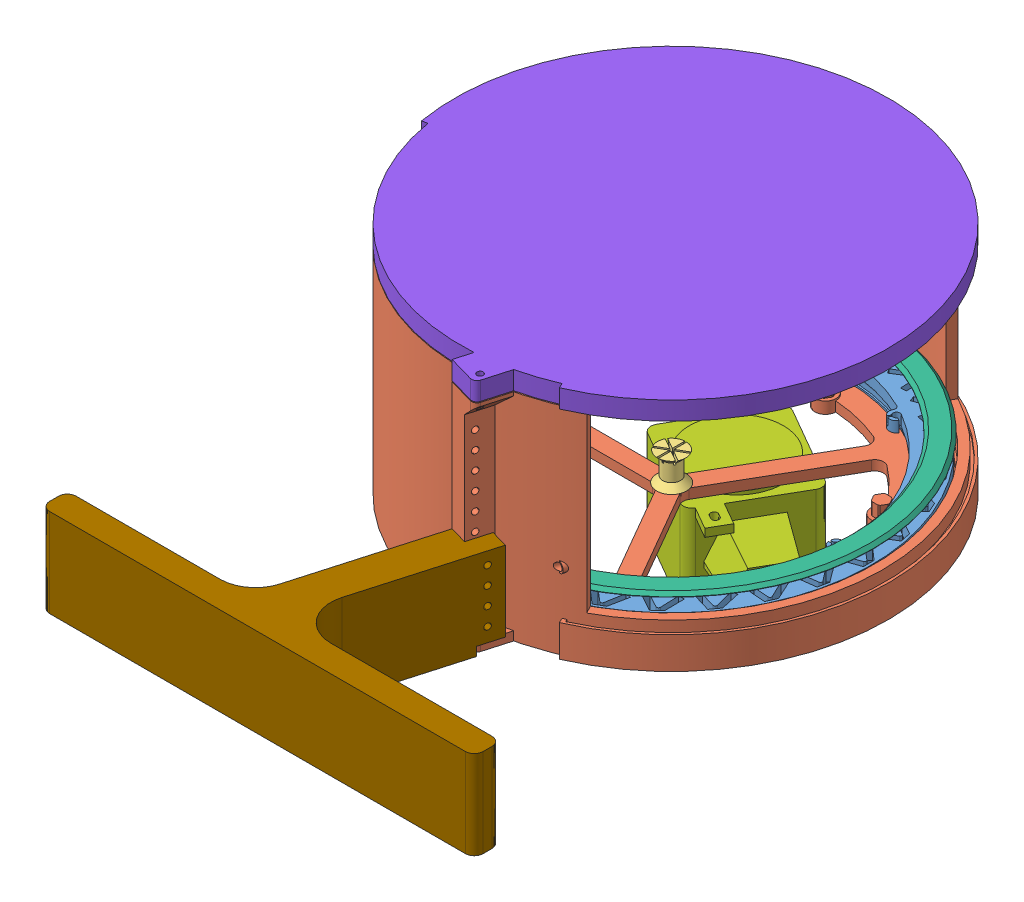
SolidWorks assembly 多色模块-装配体, configuration 默认. Lengths in mm.
Overall size (362.98 195.67 356.44).
17 component instances, 16 part files, 16 mates.
Components (placement in the parent):
- 卡爪-1: 卡爪 [默认] at origin size (224.72 94.33 198.11) (hidden)
- 托盘-2: 托盘 [默认] at origin size (225.72 151.25 225.72)
- 外筒-1: 外筒 [默认] at origin size (293.71 127.25 345.86)
- 外筒-2: 外筒 [默认] at (0 122.153 0) size (293.71 127.25 345.86) (hidden)
- 门-1: 门 [默认] at origin size (74.09 107 231.08) (hidden)
- 回转爪-1: 回转爪 [默认] at origin size (352.65 71.3 16.8)
- 阻尼轴-2: 阻尼轴 [默认] at (-0.2 -13 -0.1155) size (5.5 7 6.35)
- 608轴承-1: 608轴承 [默认] at (-75.2595 -15.2 -43.4511) size (22 42.33 22)
- 挡环-1: 挡环 [默认] at origin size (227.52 2 227.52)
- 模块化挤出机-1: 模块化挤出机 [默认] at (5.5296 17 187.6364) x (0 1 0) z (-0.275449 0 0.961316) size (62.4 10 62.4) (hidden)
- CR20挤出机-1: CR20挤出机 [默认] at (5.5296 17 187.6364) x (0.275449 0 -0.961316) z (0 -1 0) size (72 25 57) (hidden)
- 挤出机连接-1: 挤出机连接 [默认] at origin size (20.98 123.75 48.47) (hidden)
- 挤出机支撑-1: 挤出机支撑 [默认] at origin
- Octopus_Pro - beta简化-1: Octopus_Pro - beta简化 [默认] at (-539.2933 -519.147 155.4731) size (162.15 99.88 19.4) (hidden)
- ptc-1: ptc [默认] at (-12.2337 -33.953 -48.8105) x (-0.866025 0 -0.5) z (0.5 0 -0.866025) size (103 52 60)
- 盖-1: 盖 [默认] at origin size (244.92 10.4 255.45)
- 底座增稳-1: 底座增稳 [默认] at origin size (244.92 50 115)
Mates (geometry in assembly coordinates):
- 距离1: distance = 0.2 mm anti-aligned: plane of 外筒-1 through (-114.3607 100 0) normal (0 1 0); plane of 外筒-2 through (-119.3607 100.2 0) normal (0 -1 0)
- 距离3: distance = 0.2 mm anti-aligned: plane of 外筒-1 through (0 -20.2 0) normal (0 1 0); plane of 阻尼轴-2 through (-0.2 -20 -0.1155) normal (0 -1 0)
- 距离4: distance = 0.2 mm anti-aligned: plane of 外筒-1 through (0 -20.2 3.1754) normal (-0.5 0 -0.866025); plane of 阻尼轴-2 through (2.55 -20 1.4722) normal (0.5 0 0.866025)
- 距离5: distance = 0.2 mm anti-aligned: plane of 外筒-1 through (2.75 -20.2 1.5877) normal (-1 0 0); plane of 阻尼轴-2 through (2.55 -20 -1.7032) normal (1 0 0)
- 距离9: distance = 0.2 mm anti-aligned: plane of 外筒-1 through (-75.2595 -15.4 -43.4511) normal (0 1 0); plane of 608轴承-1 through (-79.2595 -15.2 -43.4511) normal (0 -1 0)
- 同心2: concentric aligned: cylinder of 外筒-1 through (-75.2595 -38.9235 -43.4511) axis (0 1 0) radius 6; cylinder of 608轴承-1 through (-75.2595 4.1457 -43.4511) axis (0 1 0) radius 4
- 同心3: concentric aligned: cylinder of 外筒-1 through (0 0 0) axis (0 1 0) radius 114.3607; cylinder of 外筒-2 through (0 122.153 0) axis (0 1 0) radius 114.3607
- 平行1: parallel anti-aligned: plane of 外筒-1 through (-33.7317 0 117.7234) normal (-0.275449 0 0.961316); plane of 模块化挤出机-1 through (4.5105 -14.2 154.8888) normal (0.275449 0 -0.961316)
- 平行2: parallel anti-aligned: plane of 外筒-1 through (0 0 0) normal (0 1 0); plane of 模块化挤出机-1 through (4.5105 -14.2 154.8888) normal (0 -1 0)
- 重合3: coincident anti-aligned: plane of 模块化挤出机-1 through (5.5296 17 187.6364) normal (0.961316 0 0.275449); plane of CR20挤出机-1 through (5.5296 17 187.6364) normal (-0.961316 0 -0.275449)
- 同心6: concentric anti-aligned: line of 外筒-1 through (72.0987 21 20.6587) axis (-0.275449 0 0.961316); cylinder of CR20挤出机-1 through (12.9169 21 227.2028) axis (0.275449 0 -0.961316) radius 2.5
- 同心7: concentric anti-aligned: cylinder of 模块化挤出机-1 through (5.5306 17 187.6367) axis (-0.961316 0 -0.275449) radius 12; cylinder of CR20挤出机-1 through (5.5287 17 187.6361) axis (0.961316 0 0.275449) radius 12
- 同心8: concentric anti-aligned: cylinder of 模块化挤出机-1 through (9.8 1.5 172.7363) axis (-0.961316 0 -0.275449) radius 1.6; cylinder of CR20挤出机-1 through (9.7981 1.5 172.7357) axis (0.961316 0 0.275449) radius 1.6
- 距离11: distance = 50 mm anti-aligned: plane of CR20挤出机-1 through (32.7495 21 157.9871) normal (0.275449 0 -0.961316); plane of 外筒-1 through (46.5219 21 109.9213) normal (-0.275449 0 0.961316)
- 距离13: distance = 10 mm anti-aligned: plane of ptc-1 through (-12.2337 -31.953 -48.8105) normal (0 1 0); plane of 外筒-1 through (-105.9607 -21.953 0) normal (0 -1 0)
- 距离14: distance = 10 mm aligned: plane of ptc-1 through (-1.253 -83.953 -7.8298) normal (0.866025 0 0.5); plane of 外筒-1 through (4.3301 79.2931 2.5) normal (0.866025 0 0.5)
